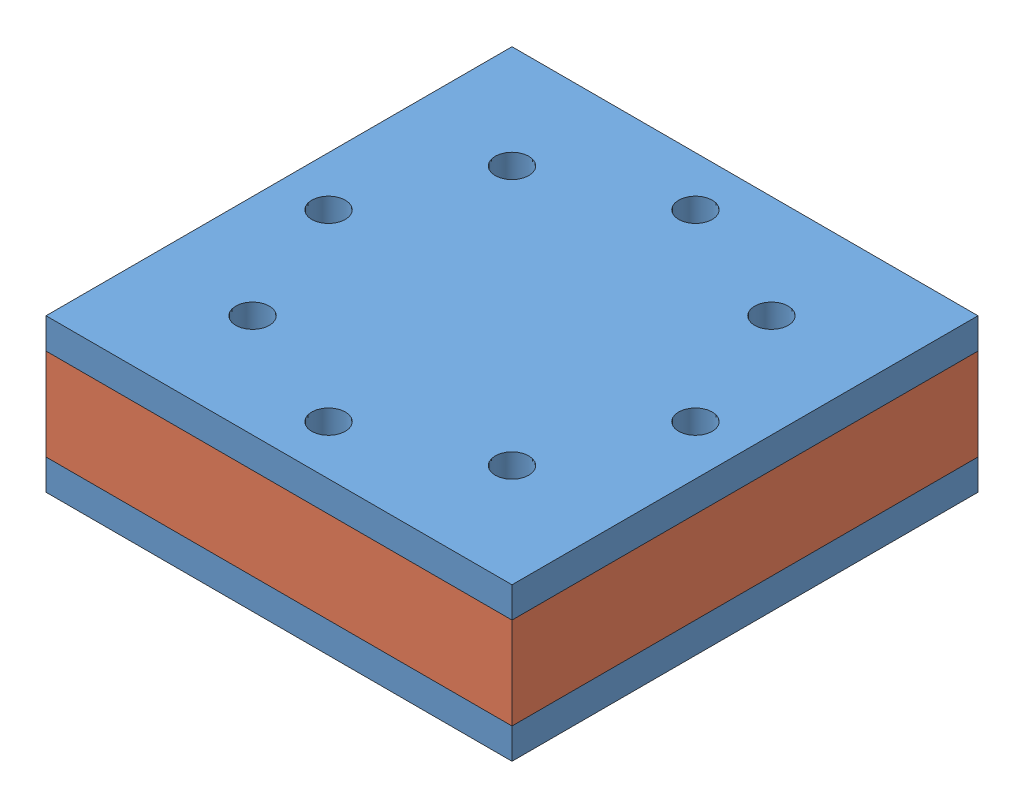
SolidWorks assembly Bolt Project Assy, configuration v4. Lengths in mm.
Overall size (152.4 50 152.4).
3 component instances, 2 part files, 9 mates.
Components (placement in the parent):
- Aluminum Plate-1: Aluminum Plate [Default] at origin size (152.4 10 152.4)
- Steel Plate-1: Steel Plate [Default] at (0 10 0) size (152.4 30 152.4)
- Aluminum Plate-2: Aluminum Plate [Default] at (0 40 0) size (152.4 10 152.4)
Mates (geometry in assembly coordinates):
- Coincident1: coincident aligned: plane of Aluminum Plate-1 through (0 0 0) normal (0 1 0)
- Coincident3: coincident aligned: plane of Aluminum Plate-1 through (0 0 0) normal (1 0 0)
- Coincident4: coincident aligned: plane of Aluminum Plate-1 through (0 0 0) normal (0 0 1)
- Coincident5: coincident anti-aligned: plane of Aluminum Plate-1 through (0 10 0) normal (0 1 0); plane of Steel Plate-1 through (0 10 0) normal (0 -1 0)
- Coincident6: coincident anti-aligned: plane of Steel Plate-1 through (0 40 0) normal (0 1 0); plane of Aluminum Plate-2 through (0 40 0) normal (0 -1 0)
- Coincident7: coincident aligned: plane of Aluminum Plate-1 through (-76.2 10 76.2) normal (0 0 1); plane of Steel Plate-1 through (-76.2 40 76.2) normal (0 0 1)
- Coincident8: coincident aligned: plane of Aluminum Plate-1 through (-76.2 10 76.2) normal (0 0 1); plane of Aluminum Plate-2 through (-76.2 50 76.2) normal (0 0 1)
- Coincident9: coincident aligned: plane of Aluminum Plate-1 through (76.2 10 76.2) normal (1 0 0); plane of Steel Plate-1 through (76.2 40 76.2) normal (1 0 0)
- Coincident10: coincident aligned: plane of Aluminum Plate-1 through (76.2 10 76.2) normal (1 0 0); plane of Aluminum Plate-2 through (76.2 50 76.2) normal (1 0 0)
